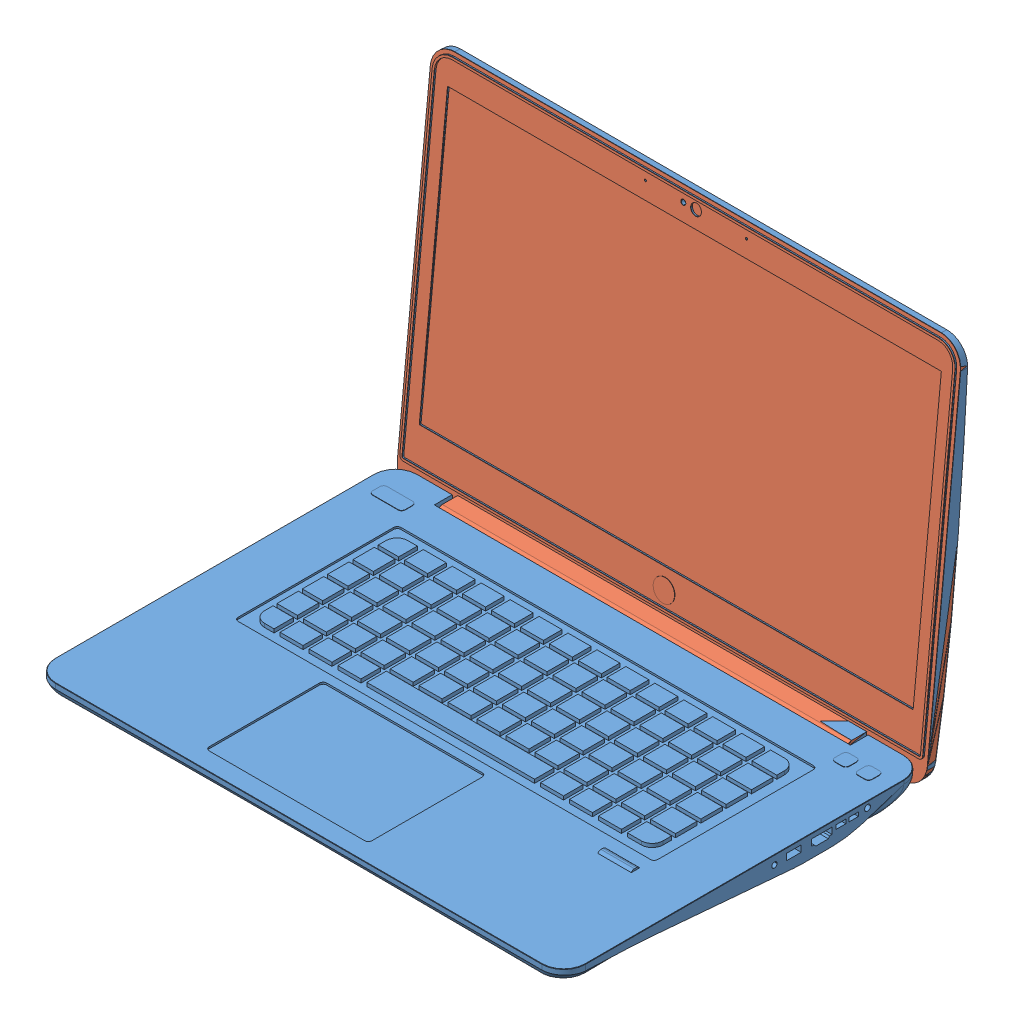
SolidWorks assembly NOTEBOOK PRO, configuration Default. Lengths in mm.
Overall size (379.93 261.56 289.32).
3 component instances, 2 part files, 0 mates.
Components (placement in the parent):
- NOTEBOOK PRO.STEP-1: NOTEBOOK PRO.STEP [Default] at origin size (379.93 261.56 289.32)
  - BASE.STEP-1: BASE.STEP [Default] at (80.1391 60.3531 339.4434) size (379.93 261.56 289.32)
  - SCREEN.STEP-1: SCREEN.STEP [Default] at (80.1391 60.3531 339.7279) size (372.12 259.03 42.96)
